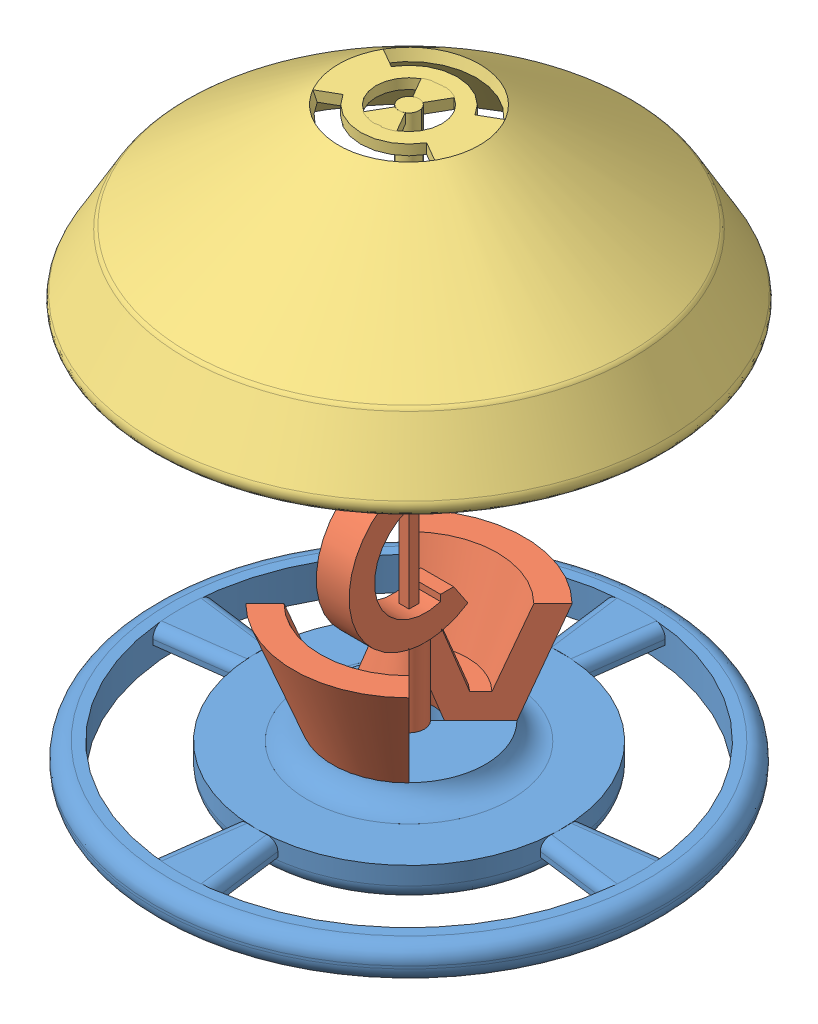
SolidWorks assembly Assem2, configuration Default. Lengths in mm.
Overall size (129.91 1597.31 128.05).
3 component instances, 3 part files, 3 mates.
Components (placement in the parent):
- Base fixed(lamp)-1: Base fixed(lamp) [Default] at origin size (127 1597.31 127)
- Mid (lamp)-2: Mid (lamp) [Default] at (-0.0148 12.573 0.0172) x (0 0 -1) z (1 0 0) size (57.65 109.73 40.77)
- Top (lamp)-1: Top (lamp) [Default] at (-0.029 12.573 -0.013) size (129.91 44.27 128.05)
Mates (geometry in assembly coordinates):
- Coincident11: coincident: plane of assembly; plane of Base fixed(lamp)-1 through (0 0 0) normal (1 0 0); point of assembly
- Coincident6: coincident anti-aligned: plane of Base fixed(lamp)-1 through (0 4.445 0) normal (0 1 0); plane of Mid (lamp)-2 through (-0.0148 4.445 0.0172) normal (0 -1 0)
- Coincident12: coincident anti-aligned: plane of Mid (lamp)-2 through (-0.0148 114.173 0.0172) normal (0 1 0); plane of Top (lamp)-1 through (-0.029 114.173 -0.013) normal (0 -1 0)
